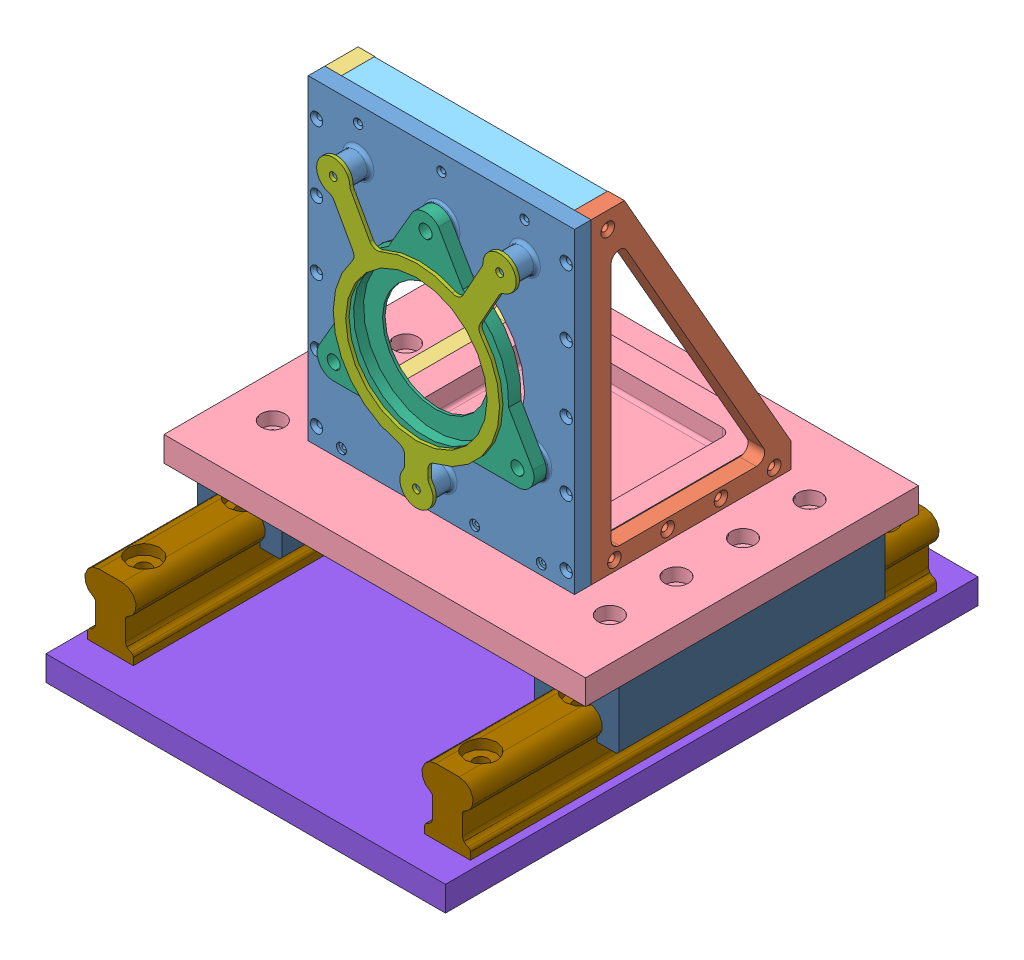
SolidWorks assembly toolbox-tutorial, configuration Default. Lengths in mm.
Overall size (321.69 351.78 406.4).
12 component instances, 10 part files, 31 mates.
Components (placement in the parent):
- frontplate-1: frontplate [Default] at (50.8 110.4814 244.4025) size (203.2 241.3 29.21)
- braceleft-1: braceleft [Default] at (241.3 110.4814 244.4025) x (0 0 -1) z (1 0 0) size (152.4 241.3 12.7)
- braceright-1: braceright [Default] at (50.8 110.4814 244.4025) x (0 0 -1) z (1 0 0) size (152.4 241.3 12.7)
- baseplate-1: baseplate [Default] at (-31.9265 110.4814 -158.66) x (1 0 0) z (0 -1 0) size (321.69 254 34.92)
- crossbar-1: crossbar [Default] at (50.8 136.2814 244.4025) x (-1 0 0) z (0 0 -1) size (177.8 25 25)
- lensholder-1: lensholder [Default] at (152.4 224.7814 259.6425) x (0 1 0) z (0 0 1) size (157.11 165.55 9.53)
- filterholder-1: filterholder [Default] at (152.4 139.0564 273.6125) size (152.4 200.02 2.54)
- table-1: table [Default] at (76.5912 0 305.9996) x (0 0 -1) z (0 1 0) size (406.4 304.8 19.05)
- rail-1: rail [left] at (6.35 19.05 25.4) size (39.12 50.8 355.6)
- rail-2: rail [right] at (263.525 19.05 25.4) size (39.12 50.8 355.6)
- slider-1: slider [left] at (60.0609 79.9184 79.3025) size (64.52 44.45 203.2)
- slider-3: slider [right] at (317.2359 79.9184 79.3025) size (64.52 44.45 203.2)
Mates (geometry in assembly coordinates):
- Coincident1: coincident anti-aligned: plane of frontplate-1 through (152.4 305.6942 259.6425) normal (0 0 1); plane of lensholder-1 through (152.4 224.7814 259.6425) normal (0 0 -1)
- Concentric1: concentric aligned: cylinder of frontplate-1 through (152.4 305.6942 259.6425) axis (0 0 -1) radius 12.7; cylinder of lensholder-1 through (152.4 305.6942 269.1675) axis (0 0 -1) radius 12.7
- Parallel1: parallel aligned: line of frontplate-1 through (50.8 110.4814 257.1025) axis (1 0 0); line of lensholder-1 through (80.4168 171.7696 269.1675) axis (1 0 0)
- Coincident2: coincident anti-aligned: plane of frontplate-1 through (215.9 313.6814 273.6125) normal (0 0 1); plane of filterholder-1 through (98.4238 269.1164 273.6125) normal (0 0 -1)
- Concentric2: concentric aligned: cylinder of frontplate-1 through (215.9 313.6814 273.6125) axis (0 0 -1) radius 9.525; cylinder of filterholder-1 through (215.9 313.6814 276.1525) axis (0 0 -1) radius 12.7
- Coincident3: coincident anti-aligned: plane of frontplate-1 through (50.8 351.7814 244.4025) normal (0 0 -1); plane of braceright-1 through (63.5 110.4814 244.4025) normal (0 0 1)
- Coincident4: coincident aligned: line of frontplate-1 through (50.8 351.7814 244.4025) axis (0 -1 0); line of braceright-1 through (50.8 351.7814 244.4025) axis (0 -1 0)
- Coincident5: coincident: point of frontplate-1; point of braceright-1
- Coincident6: coincident anti-aligned: plane of frontplate-1 through (50.8 351.7814 244.4025) normal (0 0 -1); plane of braceleft-1 through (254 110.4814 244.4025) normal (0 0 1)
- Coincident7: coincident anti-aligned: line of frontplate-1 through (254 110.4814 244.4025) axis (0 1 0); line of braceleft-1 through (254 351.7814 244.4025) axis (0 -1 0)
- Coincident8: coincident: point of frontplate-1; point of braceleft-1
- Coincident9: coincident anti-aligned: plane of frontplate-1 through (50.8 110.4814 257.1025) normal (0 -1 0); plane of baseplate-1 through (-8.4455 110.4814 53.9025) normal (0 1 0)
- Coincident10: coincident anti-aligned: plane of braceright-1 through (63.5 351.7814 244.4025) normal (1 0 0); plane of baseplate-1 through (63.5 126.3564 233.6139) normal (-1 0 0)
- Coincident11: coincident anti-aligned: plane of frontplate-1 through (50.8 351.7814 244.4025) normal (0 0 -1); plane of baseplate-1 through (73.2155 126.3564 244.4025) normal (0 0 1)
- Coincident12: coincident anti-aligned: plane of frontplate-1 through (50.8 351.7814 244.4025) normal (0 0 -1); plane of crossbar-1 through (63.5 326.7814 244.4025) normal (0 0 1)
- Coincident13: coincident anti-aligned: line of frontplate-1 through (254 351.7814 244.4025) axis (-1 0 0); line of crossbar-1 through (63.5 351.7814 244.4025) axis (1 0 0)
- Coincident14: coincident: line of braceleft-1 through (241.3 351.7814 219.0025) axis (0 0 1); point of crossbar-1
- Distance8: distance = 6.35 mm aligned: plane of table-1 through (0 19.05 406.4) normal (-1 0 0); plane of rail-1 through (6.35 19.05 381) normal (-1 0 0)
- Coincident40: coincident anti-aligned: plane of table-1 through (0 19.05 406.4) normal (0 1 0); plane of rail-1 through (6.35 19.05 381) normal (0 -1 0)
- Distance9: distance = 25.4 mm aligned: plane of table-1 through (304.8 19.05 406.4) normal (0 0 1); plane of rail-1 through (8.89 24.5201 381) normal (0 0 1)
- Distance10: distance = 6.35 mm aligned: plane of table-1 through (304.8 19.05 406.4) normal (1 0 0); plane of rail-2 through (298.45 19.05 381) normal (1 0 0)
- Coincident45: coincident anti-aligned: plane of table-1 through (0 19.05 406.4) normal (0 1 0); plane of rail-2 through (263.525 19.05 381) normal (0 -1 0)
- Coincident46: coincident aligned: plane of rail-1 through (8.89 24.5201 381) normal (0 0 1); plane of rail-2 through (266.065 24.5201 381) normal (0 0 1)
- Concentric4: concentric aligned: cylinder of rail-1 through (14.9225 59.182 381) axis (0 0 -1) radius 10.668; cylinder of slider-1 through (14.9225 59.182 282.5025) axis (0 0 -1) radius 10.668
- Concentric5: concentric aligned: cylinder of rail-1 through (32.7025 59.182 381) axis (0 0 -1) radius 10.668; cylinder of slider-1 through (32.7025 59.182 282.5025) axis (0 0 -1) radius 10.668
- Concentric6: concentric aligned: cylinder of rail-2 through (272.0975 59.182 381) axis (0 0 -1) radius 10.668; cylinder of slider-3 through (272.0975 59.182 282.5025) axis (0 0 -1) radius 10.668
- Concentric7: concentric aligned: cylinder of rail-2 through (289.8775 59.182 381) axis (0 0 -1) radius 10.668; cylinder of slider-3 through (289.8775 59.182 282.5025) axis (0 0 -1) radius 10.668
- Coincident47: coincident aligned: plane of slider-1 through (14.9225 59.182 282.5025) normal (0 0 1); plane of slider-3 through (272.0975 59.182 282.5025) normal (0 0 1)
- Coincident48: coincident anti-aligned: plane of baseplate-1 through (-8.4455 91.4314 53.9025) normal (0 -1 0); plane of slider-3 through (248.7295 91.4314 282.5025) normal (0 1 0)
- Coincident49: coincident anti-aligned: line of baseplate-1 through (313.2455 91.4314 53.9025) axis (0 0 1); line of slider-3 through (313.2455 91.4314 282.5025) axis (0 0 -1)
- Distance11: distance = 25.4 mm aligned: plane of baseplate-1 through (-8.4455 91.4314 307.9025) normal (0 0 1); plane of slider-1 through (14.9225 59.182 282.5025) normal (0 0 1)
